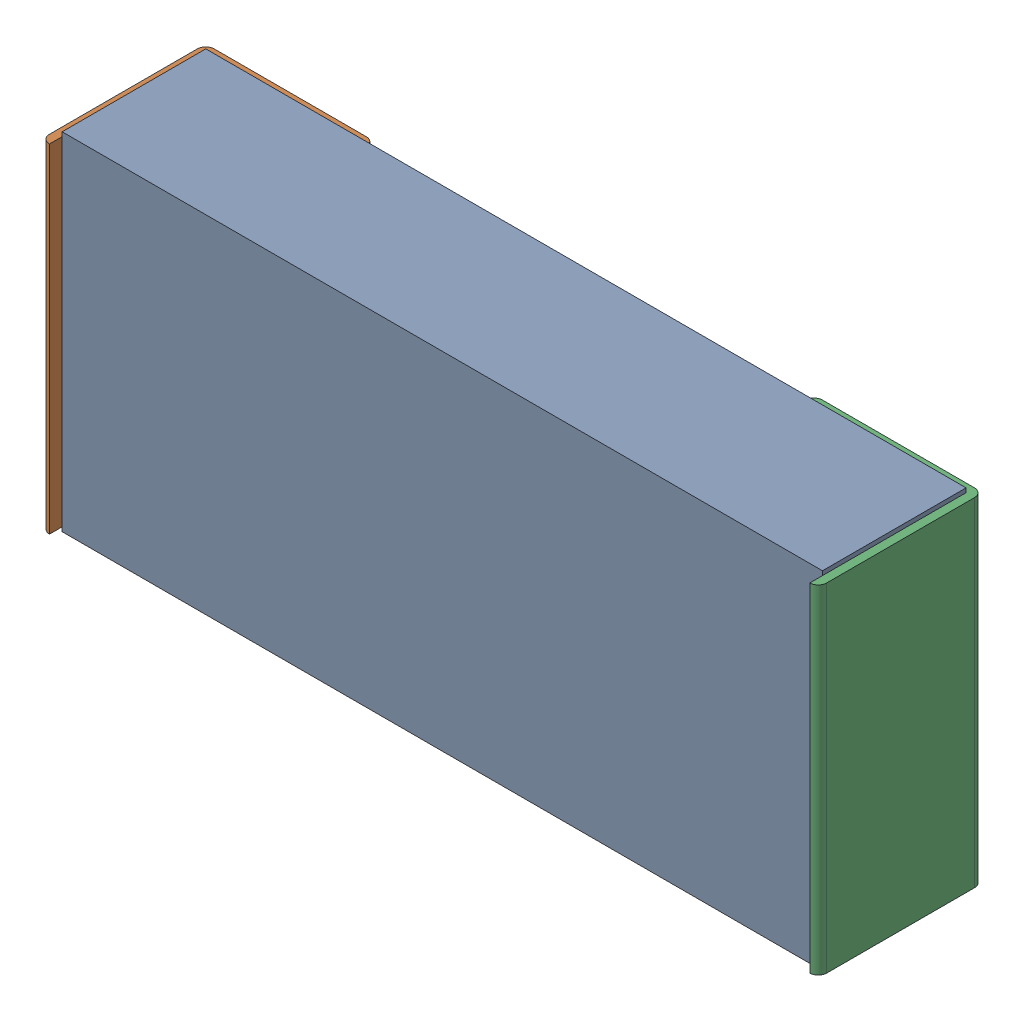
SolidWorks assembly R1, configuration Predeterminado. Lengths in mm.
Overall size (2.34 1.04 0.5).
4 component instances, 3 part files, 0 mates.
Components (placement in the parent):
- Open CASCADE STEP translator 6.8 1.13.1-1: Open CASCADE STEP translator 6.8 1.13.1 [Predeterminado] at origin size (2.34 1.04 0.5)
  - Body_1_5-1: Body_1_5 [Predeterminado] at origin size (2.29 1.04 0.43)
  - Pin_1_4-1: Pin_1_4 [Predeterminado] at (0.3048 0 0) x (-1 0 0) z (0 0 1) size (0.51 1.02 0.5)
  - Pin_2_4-1: Pin_2_4 [Predeterminado] at origin size (0.51 1.02 0.5)
